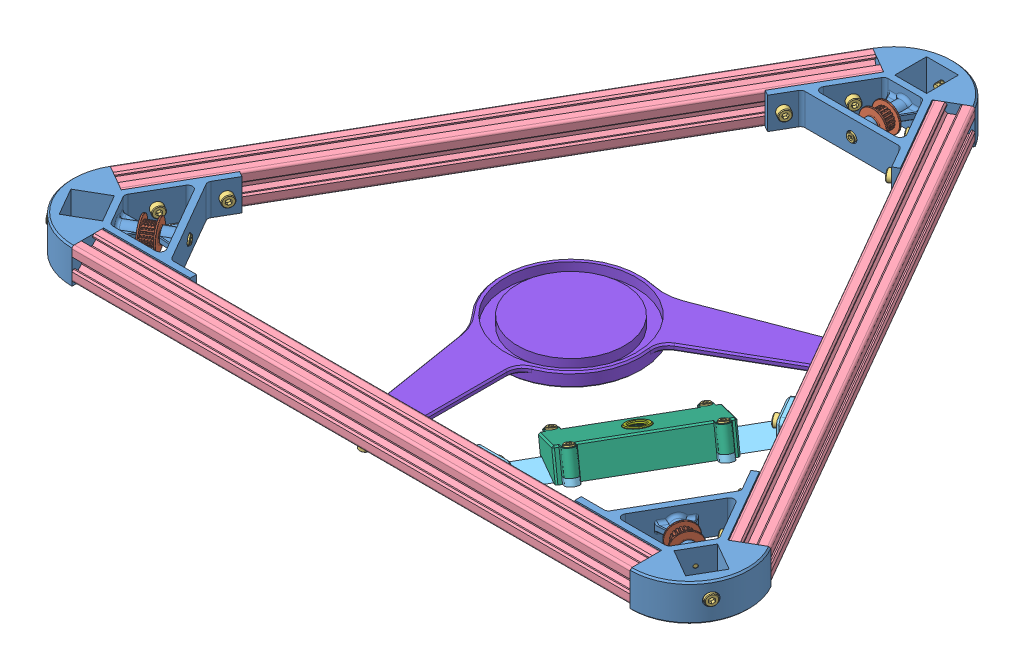
SolidWorks assembly Top Assembly, configuration Default. Lengths in mm.
Overall size (443.23 35.14 418.99).
43 component instances, 8 part files, 28 mates.
Components (placement in the parent):
- Timing Assembly-1: Timing Assembly [Default] at origin size (92.71 23 94.2)
  - Top Corner Support-1: Top Corner Support [Default] at origin size (92.71 23 94.2)
  - Timing Pulley-1: Timing Pulley [Default] at (58.7441 9.7289 -33.9159) x (0.494167 0.152298 0.855923) z (-0.866025 0 0.5) size (17.85 17.85 9.2)
  - socket head cap screw_am-1: socket head cap screw_am [B18.3.1M - 3 x 0.5 x 35 Hex SHCS -- 18SHX] at (72.0353 9.7289 -41.5896) x (-0.866025 0 0.5) z (-0.435421 -0.491563 -0.754171) size (38 5.5 5.5)
  - socket head cap screw_am-2: socket head cap screw_am [B18.3.1M - 4 x 0.7 x 8 Hex SHCS -- 8SHX] at (95.7707 10 -18) x (0 0 1) z (-0.923728 -0.383049 0) size (12 7 7)
  - socket head cap screw_am-3: socket head cap screw_am [B18.3.1M - 4 x 0.7 x 8 Hex SHCS -- 8SHX] at (63.4876 10 -18) x (0 0 1) z (-0.923728 -0.383049 0) size (12 7 7)
  - socket head cap screw_am-4: socket head cap screw_am [B18.3.1M - 4 x 0.7 x 8 Hex SHCS -- 8SHX] at (47.3323 10 -45.9819) x (-0.866025 0 -0.5) z (-0.190925 0.924225 0.330691) size (12 7 7)
  - socket head cap screw_am-5: socket head cap screw_am [B18.3.1M - 4 x 0.7 x 8 Hex SHCS -- 8SHX] at (63.4738 10 -73.9399) x (-0.866025 0 -0.5) z (-0.190925 0.924225 0.330691) size (12 7 7)
  - socket head cap screw_am-6: socket head cap screw_am [B18.3.1M - 4 x 0.7 x 8 Hex SHCS -- 8SHX] at (14.3627 10 -8.2923) x (0.866025 0 -0.5) z (0.5 0 0.866025) size (12 7 7)
- Horizontal Extrusion-1: Horizontal Extrusion [Default] at (402 10 0) x (0 0 1) z (-1 0 0) size (20 20 354)
- Horizontal Extrusion-2: Horizontal Extrusion [Default] at (201 10 -348.1422) x (0.866025 0 0.5) z (-0.5 0 0.866025) size (20 20 354)
- Timing Assembly-2: Timing Assembly [Default] at (450 0 0) x (-0.5 0 -0.866025) z (0.866025 0 -0.5) size (92.71 23 94.2)
  - Top Corner Support-1: Top Corner Support [Default] at origin size (92.71 23 94.2)
  - Timing Pulley-1: Timing Pulley [Default] at (58.7441 9.7289 -33.9159) x (0.494167 0.152298 0.855923) z (-0.866025 0 0.5) size (17.85 17.85 9.2)
  - socket head cap screw_am-1: socket head cap screw_am [B18.3.1M - 3 x 0.5 x 35 Hex SHCS -- 18SHX] at (72.0353 9.7289 -41.5896) x (-0.866025 0 0.5) z (-0.435421 -0.491563 -0.754171) size (38 5.5 5.5)
  - socket head cap screw_am-2: socket head cap screw_am [B18.3.1M - 4 x 0.7 x 8 Hex SHCS -- 8SHX] at (95.7707 10 -18) x (0 0 1) z (-0.923728 -0.383049 0) size (12 7 7)
  - socket head cap screw_am-3: socket head cap screw_am [B18.3.1M - 4 x 0.7 x 8 Hex SHCS -- 8SHX] at (63.4876 10 -18) x (0 0 1) z (-0.923728 -0.383049 0) size (12 7 7)
  - socket head cap screw_am-4: socket head cap screw_am [B18.3.1M - 4 x 0.7 x 8 Hex SHCS -- 8SHX] at (47.3323 10 -45.9819) x (-0.866025 0 -0.5) z (-0.190925 0.924225 0.330691) size (12 7 7)
  - socket head cap screw_am-5: socket head cap screw_am [B18.3.1M - 4 x 0.7 x 8 Hex SHCS -- 8SHX] at (63.4738 10 -73.9399) x (-0.866025 0 -0.5) z (-0.190925 0.924225 0.330691) size (12 7 7)
  - socket head cap screw_am-6: socket head cap screw_am [B18.3.1M - 4 x 0.7 x 8 Hex SHCS -- 8SHX] at (14.3627 10 -8.2923) x (0.866025 0 -0.5) z (0.5 0 0.866025) size (12 7 7)
- Timing Assembly-3: Timing Assembly [Default] at (225 0 -389.7114) x (-0.5 0 0.866025) z (-0.866025 0 -0.5) size (92.71 23 94.2)
  - Top Corner Support-1: Top Corner Support [Default] at origin size (92.71 23 94.2)
  - Timing Pulley-1: Timing Pulley [Default] at (58.7441 9.7289 -33.9159) x (0.494167 0.152298 0.855923) z (-0.866025 0 0.5) size (17.85 17.85 9.2)
  - socket head cap screw_am-1: socket head cap screw_am [B18.3.1M - 3 x 0.5 x 35 Hex SHCS -- 18SHX] at (72.0353 9.7289 -41.5896) x (-0.866025 0 0.5) z (-0.435421 -0.491563 -0.754171) size (38 5.5 5.5)
  - socket head cap screw_am-2: socket head cap screw_am [B18.3.1M - 4 x 0.7 x 8 Hex SHCS -- 8SHX] at (95.7707 10 -18) x (0 0 1) z (-0.923728 -0.383049 0) size (12 7 7)
  - socket head cap screw_am-3: socket head cap screw_am [B18.3.1M - 4 x 0.7 x 8 Hex SHCS -- 8SHX] at (63.4876 10 -18) x (0 0 1) z (-0.923728 -0.383049 0) size (12 7 7)
  - socket head cap screw_am-4: socket head cap screw_am [B18.3.1M - 4 x 0.7 x 8 Hex SHCS -- 8SHX] at (47.3323 10 -45.9819) x (-0.866025 0 -0.5) z (-0.190925 0.924225 0.330691) size (12 7 7)
  - socket head cap screw_am-5: socket head cap screw_am [B18.3.1M - 4 x 0.7 x 8 Hex SHCS -- 8SHX] at (63.4738 10 -73.9399) x (-0.866025 0 -0.5) z (-0.190925 0.924225 0.330691) size (12 7 7)
  - socket head cap screw_am-6: socket head cap screw_am [B18.3.1M - 4 x 0.7 x 8 Hex SHCS -- 8SHX] at (14.3627 10 -8.2923) x (0.866025 0 -0.5) z (0.5 0 0.866025) size (12 7 7)
- Horizontal Extrusion-3: Horizontal Extrusion [Default] at (249 10 -348.1422) x (0.866025 0 -0.5) z (0.5 0 0.866025) size (20 20 354)
- Camera Assembly-1: Camera Assembly [Default] at (329.7037 4 -96.7792) x (-0.5 0 0.866025) z (-0.866025 0 -0.5) size (156.29 32.1 140.07)
  - Camera Mount-1: Camera Mount [Default] at (23.6651 -4 -152.5692) x (-0.5 0 0.866025) z (-0.866025 0 -0.5) size (86.35 23.97 130.57)
  - Camera Housing-2: Camera Housing [Default] at (66.6151 1.6747 -25.5117) x (-1 0 0) z (0 0.347985 -0.9375) size (85.9 18.4 40.3)
  - socket head cap screw_am-1: socket head cap screw_am [B18.3.1M - 3 x 0.5 x 16 Hex SHCS -- 16SHX] at (-12.2849 20.9061 -21.5733) x (0 -0.9375 -0.347985) z (0.347985 -0.326236 0.878906) size (19 5.5 5.5)
  - socket head cap screw_am-2: socket head cap screw_am [B18.3.1M - 3 x 0.5 x 16 Hex SHCS -- 16SHX] at (-12.2849 9.5618 8.9892) x (0 -0.9375 -0.347985) z (-0.058173 -0.347396 0.935912) size (19 5.5 5.5)
  - socket head cap screw_am-3: socket head cap screw_am [B18.3.1M - 3 x 0.5 x 16 Hex SHCS -- 16SHX] at (59.6151 20.9061 -21.5733) x (0 -0.9375 -0.347985) z (-0.058173 -0.347396 0.935912) size (19 5.5 5.5)
  - socket head cap screw_am-4: socket head cap screw_am [B18.3.1M - 3 x 0.5 x 16 Hex SHCS -- 16SHX] at (59.6151 9.5618 8.9892) x (0 -0.9375 -0.347985) z (-0.058173 -0.347396 0.935912) size (19 5.5 5.5)
  - socket head cap screw_am-5: socket head cap screw_am [B18.3.1M - 4 x 0.7 x 8 Hex SHCS -- 8SHX] at (-39.3061 6 -7.5) x (-0.866025 0 -0.5) z (0.09665 0.98114 -0.167404) size (12 7 7)
  - socket head cap screw_am-6: socket head cap screw_am [B18.3.1M - 4 x 0.7 x 8 Hex SHCS -- 8SHX] at (86.6362 6 -7.5) x (0.866025 0 -0.5) z (0.5 0 0.866025) size (12 7 7)
  - Camera Bezel-1: Camera Bezel [Default] at (23.6651 14.9996 -6.3791) x (-0.678869 0.255512 -0.688369) z (-0.73426 -0.236236 0.636439) size (14 2 14)
- Light Bracket-1: Light Bracket [Default] at (450 -4 0) x (-0.5 0 -0.866025) z (0.866025 0 -0.5) size (166.5 9 212.67)
- socket head cap screw_am-1: socket head cap screw_am [B18.3.1M - 4 x 0.7 x 8 Hex SHCS -- 8SHX] at (337 -8 -195.7217) x (0 1 0) z (-0.546944 0 0.837169) size (12 7 7)
- socket head cap screw_am-2: socket head cap screw_am [B18.3.1M - 4 x 0.7 x 8 Hex SHCS -- 8SHX] at (224 -8 0) x (0 1 0) z (-0.546944 0 0.837169) size (12 7 7)
Mates (geometry in assembly coordinates):
- Coincident1: coincident: plane of Timing Assembly-1/Top Corner Support-1 through (84.5 20 -10) normal (0 0 1); plane of Horizontal Extrusion-1 through (48 1.5 -10) normal (0 0 -1)
- Coincident2: coincident: plane of Timing Assembly-1/Top Corner Support-1 through (48 20 10) normal (1 0 0); plane of Horizontal Extrusion-1 through (48 18.5 -8.5) normal (-1 0 0)
- Coincident3: coincident: plane of Timing Assembly-1/Top Corner Support-1 through (48 20 -27.7128) normal (0 1 0); plane of Horizontal Extrusion-1 through (48 20 -4.1) normal (0 1 0)
- Coincident4: coincident: plane of Timing Assembly-1/Top Corner Support-1 through (32.6603 20 -36.5692) normal (-0.866025 0 -0.5); plane of Horizontal Extrusion-2 through (32.6603 18.5 -36.5692) normal (0.866025 0 0.5)
- Coincident5: coincident: plane of Timing Assembly-1/Top Corner Support-1 through (15.3397 20 -46.5692) normal (0.5 0 -0.866025); plane of Horizontal Extrusion-2 through (16.6388 18.5 -45.8192) normal (-0.5 0 0.866025)
- Coincident6: coincident: plane of Timing Assembly-1/Top Corner Support-1 through (48 20 -27.7128) normal (0 1 0); plane of Horizontal Extrusion-2 through (27.5507 20 -39.5192) normal (0 1 0)
- Coincident7: coincident: plane of Horizontal Extrusion-1 through (48 18.5 -10) normal (0 0 -1); plane of Timing Assembly-2/Top Corner Support-1 through (402 20 -10) normal (0 0 1)
- Coincident8: coincident: plane of Horizontal Extrusion-1 through (402 18.5 -8.5) normal (1 0 0); plane of Timing Assembly-2/Top Corner Support-1 through (402 20 10) normal (-1 0 0)
- Coincident9: coincident: plane of Horizontal Extrusion-1 through (48 20 -4.1) normal (0 1 0); plane of Timing Assembly-2/Top Corner Support-1 through (402 20 -27.7128) normal (0 1 0)
- Coincident10: coincident: plane of Horizontal Extrusion-2 through (32.6603 18.5 -36.5692) normal (0.866025 0 0.5); plane of Timing Assembly-3/Top Corner Support-1 through (191.4103 20 -311.5323) normal (-0.866025 0 -0.5)
- Coincident11: coincident: plane of Horizontal Extrusion-2 through (193.6388 18.5 -352.3922) normal (0.5 0 -0.866025); plane of Timing Assembly-3/Top Corner Support-1 through (192.3397 20 -353.1422) normal (-0.5 0 0.866025)
- Coincident12: coincident: plane of Horizontal Extrusion-2 through (27.5507 20 -39.5192) normal (0 1 0); plane of Timing Assembly-3/Top Corner Support-1 through (225 20 -334.2858) normal (0 1 0)
- Coincident13: coincident: plane of Timing Assembly-2/Top Corner Support-1 through (399.0897 20 -68.1791) normal (0.866025 0 -0.5); plane of Horizontal Extrusion-3 through (417.3397 18.5 -36.5692) normal (-0.866025 0 0.5)
- Coincident14: coincident: plane of Timing Assembly-3/Top Corner Support-1 through (240.3397 20 -343.1422) normal (0.866025 0 -0.5); plane of Horizontal Extrusion-3 through (417.3397 18.5 -36.5692) normal (-0.866025 0 0.5)
- Coincident15: coincident: plane of Timing Assembly-3/Top Corner Support-1 through (257.6603 20 -353.1422) normal (0.5 0 0.866025); plane of Horizontal Extrusion-3 through (241.6388 18.5 -343.8922) normal (-0.5 0 -0.866025)
- Coincident16: coincident: plane of Timing Assembly-2/Top Corner Support-1 through (434.6603 20 -46.5692) normal (-0.5 0 -0.866025); plane of Horizontal Extrusion-3 through (418.6388 18.5 -37.3192) normal (0.5 0 0.866025)
- Coincident17: coincident: plane of Timing Assembly-2/Top Corner Support-1 through (402 20 -27.7128) normal (0 1 0); plane of Horizontal Extrusion-3 through (422.4493 20 -39.5192) normal (0 1 0)
- Coincident18: coincident: plane of Timing Assembly-3/Top Corner Support-1 through (225 20 -334.2858) normal (0 1 0); plane of Horizontal Extrusion-3 through (422.4493 20 -39.5192) normal (0 1 0)
- Coincident19: coincident: plane of Horizontal Extrusion-3 through (417.3397 1.5 -36.5692) normal (-0.866025 0 0.5); plane of Camera Assembly-1/Camera Mount-1 through (356.1406 4 -142.5692) normal (0.866025 0 -0.5)
- Coincident20: coincident: plane of Horizontal Extrusion-1 through (48 1.5 -10) normal (0 0 -1); plane of Camera Assembly-1/Camera Mount-1 through (303.8505 4 -10) normal (0 0 1)
- Coincident21: coincident: plane of Horizontal Extrusion-3 through (422.4493 0 -39.5192) normal (0 -1 0); plane of Camera Assembly-1/Camera Mount-1 through (450 0 0) normal (0 -1 0)
- Distance1: distance = 4 mm: plane of Light Bracket-1 through (347.1962 0 -190.0615) normal (0.866025 0 -0.5); plane of Horizontal Extrusion-3 through (434.6603 1.5 -46.5692) normal (0.866025 0 -0.5)
- Coincident23: coincident: plane of Horizontal Extrusion-3 through (422.4493 0 -39.5192) normal (0 -1 0); plane of Light Bracket-1 through (224 0 -130.4812) normal (0 1 0)
- Distance2: distance = 4 mm: plane of Light Bracket-1 through (234 0 6) normal (0 0 1); plane of Horizontal Extrusion-1 through (48 1.5 10) normal (0 0 1)
- Concentric2: concentric: cylinder of Light Bracket-1 through (337 0 -195.7217) axis (0 -1 0) radius 2.125; cylinder of socket head cap screw_am-1 through (337 -39.75 -195.7217) axis (0 -1 0) radius 3.5
- Concentric3: concentric: cylinder of Light Bracket-1 through (224 0 0) axis (0 -1 0) radius 2.125; cylinder of socket head cap screw_am-2 through (224 -39.75 0) axis (0 -1 0) radius 3.5
- Coincident25: coincident: plane of Light Bracket-1 through (224 -4 -130.4812) normal (0 -1 0); plane of socket head cap screw_am-2 through (221.0699 -4 -1.9143) normal (0 1 0)
- Coincident26: coincident: plane of Light Bracket-1 through (224 -4 -130.4812) normal (0 -1 0); plane of socket head cap screw_am-1 through (334.0699 -4 -197.636) normal (0 1 0)
